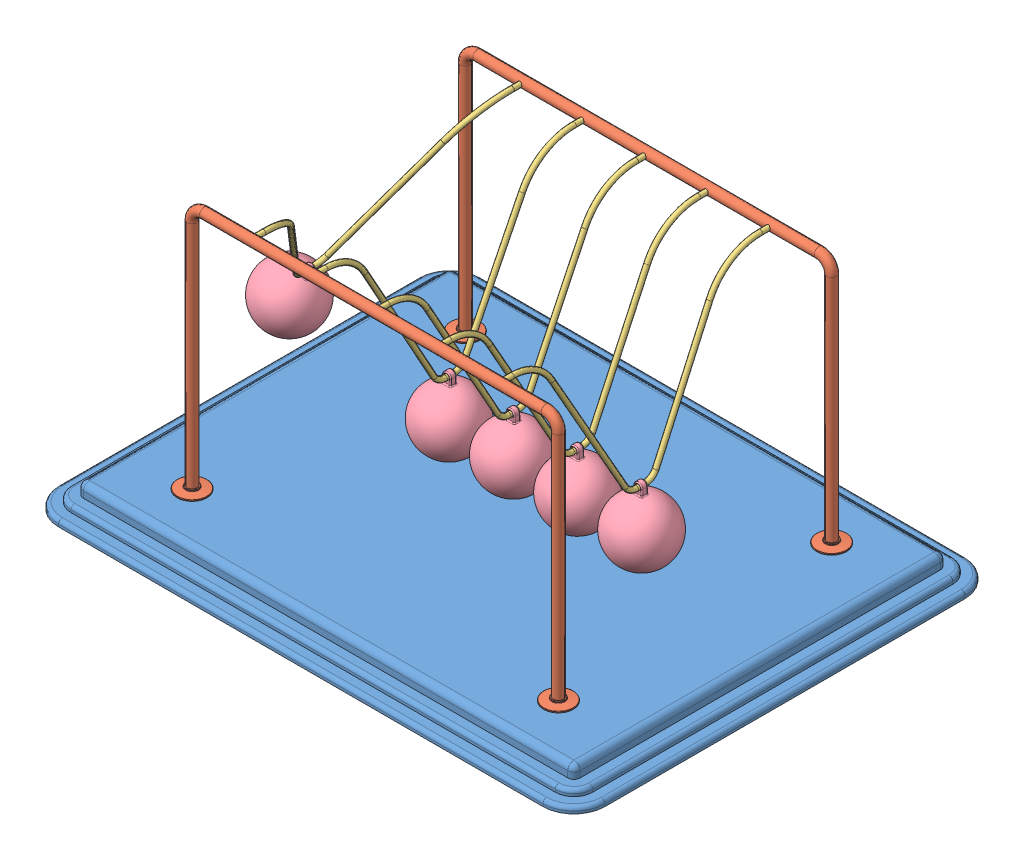
SolidWorks assembly Newtons Cradle NewtonsCradle 0253, configuration Default. Lengths in mm.
Overall size (440 222 340).
13 component instances, 4 part files, 34 mates.
Components (placement in the parent):
- Base 205.024311183144-1: Base 205.024311183144 [Default] at (-16.2968 -4.1587 11.425) size (440 20 340)
- frame NewtonsCradle 0253-1: frame NewtonsCradle 0253 [Default] at (-16.2968 144.4547 -98.575) size (319 202 24)
- frame NewtonsCradle 0253-2: frame NewtonsCradle 0253 [Default] at (-16.2968 144.4547 121.425) x (-1 0 0) z (0 0 -1) size (319 202 24)
- Hanging thing NewtonsCradle 0253-1: Hanging thing NewtonsCradle 0253 [Default] at (-157.6326 134.1825 11.425) x (0 0 1) z (-0.859985 0.510319 0) size (220 129 4)
- Hanging thing NewtonsCradle 0253-2: Hanging thing NewtonsCradle 0253 [Default] at (-66.576 122.8418 11.425) x (0 0 1) z (-0.999994 0.003446 0) size (220 129 4)
- Hanging thing NewtonsCradle 0253-3: Hanging thing NewtonsCradle 0253 [Default] at (-15.6923 122.8436 11.425) x (0 0 1) z (-0.999972 -0.007464 0) size (220 129 4)
- Hanging thing NewtonsCradle 0253-4: Hanging thing NewtonsCradle 0253 [Default] at (35.2213 122.8555 11.425) x (0 0 1) z (-0.999824 -0.018742 0) size (220 129 4)
- Hanging thing NewtonsCradle 0253-5: Hanging thing NewtonsCradle 0253 [Default] at (86.0287 122.8747 11.425) x (0 0 1) z (-0.999588 -0.028711 0) size (220 129 4)
- Sphere NewtonsCradle 0253-1: Sphere NewtonsCradle 0253 [Default] at (-195.3962 70.5436 11.425) x (0.859985 -0.510319 0) z (0 0 1) size (50 58.5 50)
- Sphere NewtonsCradle 0253-2: Sphere NewtonsCradle 0253 [Default] at (88.1533 48.9052 11.425) x (0.999588 0.028711 0) z (0 0 1) size (50 58.5 50)
- Sphere NewtonsCradle 0253-3: Sphere NewtonsCradle 0253 [Default] at (-15.14 48.8456 11.425) x (0.999972 0.007464 0) z (0 0 1) size (50 58.5 50)
- Sphere NewtonsCradle 0253-4: Sphere NewtonsCradle 0253 [Default] at (36.6081 48.8685 11.425) x (0.999824 0.018742 0) z (0 0 1) size (50 58.5 50)
- Sphere NewtonsCradle 0253-5: Sphere NewtonsCradle 0253 [Default] at (-66.831 48.8422 11.425) x (0.999994 -0.003446 0) z (0 0 1) size (50 58.5 50)
Mates (geometry in assembly coordinates):
- Coincident1: coincident anti-aligned: plane of Base-1 through (-211.2968 5.8413 156.425) normal (0 1 0); plane of frame-2 through (-175.7968 5.8413 121.425) normal (0 -1 0)
- Coincident2: coincident anti-aligned: plane of Base-1 through (-211.2968 5.8413 156.425) normal (0 1 0); plane of frame-1 through (143.2032 5.8413 -98.575) normal (0 -1 0)
- Concentric1: concentric anti-aligned: cylinder of frame-1 through (-116.2968 203.8413 -94.575) axis (0 0 -1) radius 2; cylinder of frame-2 through (-116.2968 203.8413 117.425) axis (0 0 1) radius 2
- Concentric2: concentric anti-aligned: cylinder of frame-1 through (83.7032 203.8413 -94.575) axis (0 0 -1) radius 2; cylinder of frame-2 through (83.7032 203.8413 117.425) axis (0 0 1) radius 2
- Distance1: distance = 60 mm: plane of frame-1 through (-16.2968 144.4547 -98.575) normal (0 0 1); line of Base-1 through (-211.2968 -12.1587 -158.575) axis (1 0 0)
- Distance2: distance = 60 mm: line of Base-1 through (178.7032 -12.1587 181.425) axis (-1 0 0); plane of frame-2 through (-16.2968 144.4547 121.425) normal (0 0 -1)
- Distance3: distance = 220 mm: plane of frame-2 through (-16.2968 144.4547 121.425) normal (-1 0 0); line of Base-1 through (-236.2968 -12.1587 156.425) axis (0 0 -1)
- Concentric3: concentric anti-aligned: cylinder of frame-1 through (-116.2968 203.8413 -94.575) axis (0 0 -1) radius 2; cylinder of Hanging thing-1 through (-116.2968 203.8413 111.425) axis (0 0 1) radius 2
- Concentric4: concentric anti-aligned: cylinder of frame-1 through (-116.2968 203.8413 -94.575) axis (0 0 -1) radius 2; cylinder of Hanging thing-1 through (-116.2968 203.8413 -98.575) axis (0 0 1) radius 2
- Concentric5: concentric aligned: cylinder of frame-2 through (-66.2968 203.8413 117.425) axis (0 0 1) radius 2; cylinder of Hanging thing-2 through (-66.2968 203.8413 111.425) axis (0 0 1) radius 2
- Concentric6: concentric aligned: cylinder of frame-2 through (-16.2968 203.8413 117.425) axis (0 0 1) radius 2; cylinder of Hanging thing-3 through (-16.2968 203.8413 111.425) axis (0 0 1) radius 2
- Concentric7: concentric aligned: cylinder of frame-2 through (33.7032 203.8413 117.425) axis (0 0 1) radius 2; cylinder of Hanging thing-4 through (33.7032 203.8413 111.425) axis (0 0 1) radius 2
- Concentric8: concentric aligned: cylinder of frame-2 through (83.7032 203.8413 117.425) axis (0 0 1) radius 2; cylinder of Hanging thing-5 through (83.7032 203.8413 111.425) axis (0 0 1) radius 2
- Coincident5: coincident anti-aligned: plane of frame-2 through (83.7032 203.8413 121.425) normal (0 0 -1); plane of Hanging thing-5 through (83.7032 203.8413 121.425) normal (0 0 1)
- Coincident6: coincident anti-aligned: plane of frame-2 through (33.7032 203.8413 121.425) normal (0 0 -1); plane of Hanging thing-4 through (33.7032 203.8413 121.425) normal (0 0 1)
- Coincident7: coincident anti-aligned: plane of frame-2 through (-16.2968 203.8413 121.425) normal (0 0 -1); plane of Hanging thing-3 through (-16.2968 203.8413 121.425) normal (0 0 1)
- Coincident8: coincident anti-aligned: plane of frame-2 through (-66.2968 203.8413 121.425) normal (0 0 -1); plane of Hanging thing-2 through (-66.2968 203.8413 121.425) normal (0 0 1)
- Coincident9: coincident anti-aligned: plane of frame-2 through (-116.2968 203.8413 121.425) normal (0 0 -1); plane of Hanging thing-1 through (-116.2968 203.8413 121.425) normal (0 0 1)
- Concentric9: concentric anti-aligned: cylinder of Hanging thing-1 through (-117.0163 78.8434 7.925) axis (0 0 1) radius 2; cylinder of Sphere-1 through (-117.0163 78.8434 13.925) axis (0 0 -1) radius 2
- Concentric13: concentric anti-aligned: cylinder of Hanging thing-2 through (-66.7276 78.842 7.925) axis (0 0 1) radius 2; cylinder of Sphere-5 through (-66.7276 78.842 13.925) axis (0 0 -1) radius 2
- Concentric15: concentric anti-aligned: cylinder of Hanging thing-3 through (-15.3639 78.8448 7.925) axis (0 0 1) radius 2; cylinder of Sphere-3 through (-15.3639 78.8448 13.925) axis (0 0 -1) radius 2
- Concentric16: concentric anti-aligned: cylinder of Hanging thing-5 through (87.292 78.8928 7.925) axis (0 0 1) radius 2; cylinder of Sphere-2 through (87.292 78.8928 13.925) axis (0 0 -1) radius 2
- Concentric17: concentric anti-aligned: cylinder of Hanging thing-4 through (36.0459 78.8632 7.925) axis (0 0 1) radius 2; cylinder of Sphere-4 through (36.0459 78.8632 13.925) axis (0 0 -1) radius 2
- Parallel1: parallel anti-aligned: plane of Hanging thing-1; plane of Sphere-1
- Coincident22: coincident anti-aligned: plane of Hanging thing-1; plane of Sphere-1
- Coincident12: coincident aligned: plane of Hanging thing-2 through (-66.576 122.8418 11.425) normal (0 0 1); plane of Sphere-5 through (-66.831 48.8422 11.425) normal (0 0 1)
- Coincident10: coincident aligned: plane of Hanging thing-1 through (-116.763 122.8426 11.425) normal (0 0 1); plane of Sphere-1 through (-118.5806 48.8842 11.425) normal (0 0 1)
- Coincident13: coincident anti-aligned: plane of Hanging thing-2 through (-66.576 122.8418 11.425) normal (-0.999994 0.003446 0); plane of Sphere-5 through (-66.831 48.8422 11.425) normal (0.999994 -0.003446 0)
- Coincident14: coincident anti-aligned: plane of Hanging thing-3 through (-15.6923 122.8436 11.425) normal (-0.999972 -0.007464 0); plane of Sphere-3 through (-15.14 48.8456 11.425) normal (0.999972 0.007464 0)
- Coincident15: coincident aligned: plane of Hanging thing-3 through (-15.6923 122.8436 11.425) normal (0 0 1); plane of Sphere-3 through (-15.14 48.8456 11.425) normal (0 0 1)
- Coincident18: coincident aligned: plane of Hanging thing-4 through (35.2213 122.8555 11.425) normal (0 0 1); plane of Sphere-4 through (36.6081 48.8685 11.425) normal (0 0 1)
- Coincident19: coincident anti-aligned: plane of Hanging thing-4 through (35.2213 122.8555 11.425) normal (-0.999824 -0.018742 0); plane of Sphere-4 through (36.6081 48.8685 11.425) normal (0.999824 0.018742 0)
- Coincident20: coincident anti-aligned: plane of Hanging thing-5 through (86.0287 122.8747 11.425) normal (-0.999588 -0.028711 0); plane of Sphere-2 through (88.1533 48.9052 11.425) normal (0.999588 0.028711 0)
- Coincident21: coincident aligned: plane of Hanging thing-5 through (86.0287 122.8747 11.425) normal (0 0 1); plane of Sphere-2 through (88.1533 48.9052 11.425) normal (0 0 1)
